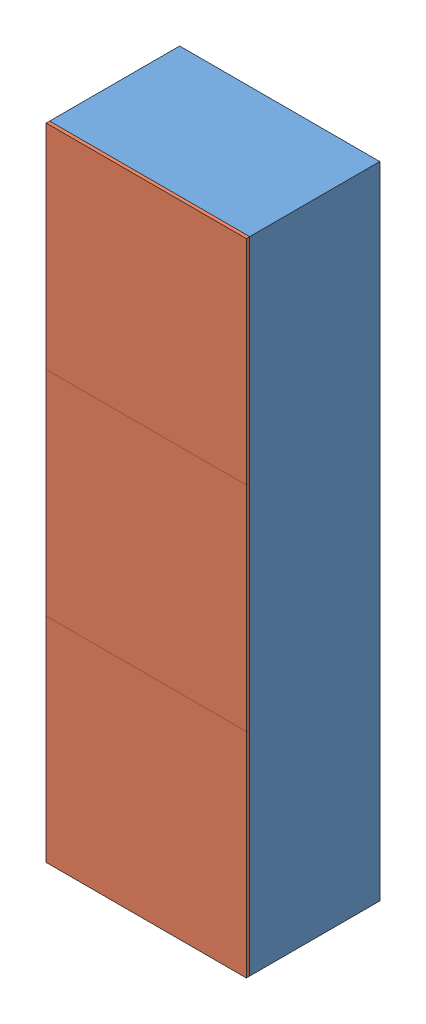
SolidWorks assembly Schrank-R, configuration Standard. Lengths in mm.
Overall size (600 1920 400).
6 component instances, 3 part files, 15 mates.
Components (placement in the parent):
- Schrank-Korpus-1: Schrank-Korpus [Standard] at (68.177 -29.4401 1725) size (600 1920 390)
- Türe-1: Türe [Standard] at (68.177 -669.4401 2115) size (600 640 10)
- Türe-2: Türe [Standard] at (68.177 -29.4401 2115) size (600 640 10)
- Türe-3: Türe [Standard] at (68.177 610.5599 2115) size (600 640 10)
- Regalbrett-1: Regalbrett [Standard] at (68.177 -354.4401 2095) x (1 0 0) z (0 1 0) size (560 360 10)
- Regalbrett-2: Regalbrett [Standard] at (68.177 285.5599 2095) x (1 0 0) z (0 1 0) size (560 360 10)
Mates (geometry in assembly coordinates):
- Deckungsgleich1: coincident: plane of Schrank-Korpus-1 through (68.177 -29.4401 1735) normal (0 0 1); plane of Regalbrett-2 through (68.177 285.5599 1735) normal (0 0 -1)
- Deckungsgleich2: coincident anti-aligned: plane of Schrank-Korpus-1 through (-211.823 910.5599 2115) normal (1 0 0); plane of Regalbrett-2 through (-211.823 290.5599 1735) normal (-1 0 0)
- Deckungsgleich3: coincident anti-aligned: plane of Schrank-Korpus-1 through (68.177 -29.4401 1735) normal (0 0 1); plane of Regalbrett-1 through (68.177 -354.4401 1735) normal (0 0 -1)
- Deckungsgleich4: coincident anti-aligned: plane of Schrank-Korpus-1 through (-211.823 910.5599 2115) normal (1 0 0); plane of Regalbrett-1 through (-211.823 -349.4401 1735) normal (-1 0 0)
- Deckungsgleich5: coincident aligned: plane of Schrank-Korpus-1 through (368.177 -989.4401 1735) normal (1 0 0); plane of Türe-1 through (368.177 -989.4401 2125) normal (1 0 0)
- Deckungsgleich6: coincident aligned: plane of Schrank-Korpus-1 through (-231.823 -989.4401 1735) normal (0 -1 0); plane of Türe-1 through (-231.823 -989.4401 2125) normal (0 -1 0)
- Deckungsgleich7: coincident: plane of Schrank-Korpus-1 through (368.177 -989.4401 1735) normal (1 0 0); plane of Türe-2 through (368.177 -349.4401 2125) normal (1 0 0)
- Deckungsgleich8: coincident anti-aligned: plane of Türe-1 through (-231.823 -349.4401 2125) normal (0 1 0); plane of Türe-2 through (-231.823 -349.4401 2125) normal (0 -1 0)
- Deckungsgleich9: coincident: plane of Schrank-Korpus-1 through (368.177 -989.4401 1735) normal (1 0 0); plane of Türe-3 through (368.177 290.5599 2125) normal (1 0 0)
- Deckungsgleich10: coincident: plane of Türe-2 through (-231.823 290.5599 2125) normal (0 1 0); plane of Türe-3 through (-231.823 290.5599 2125) normal (0 -1 0)
- Deckungsgleich11: coincident anti-aligned: plane of Schrank-Korpus-1 through (68.177 -29.4401 2115) normal (0 0 1); plane of Türe-1 through (68.177 -669.4401 2115) normal (0 0 -1)
- Deckungsgleich12: coincident: plane of Türe-1 through (-231.823 -349.4401 2125) normal (0 1 0); plane of Regalbrett-1 through (-211.823 -349.4401 1735) normal (0 1 0)
- Deckungsgleich13: coincident anti-aligned: plane of Schrank-Korpus-1 through (68.177 -29.4401 2115) normal (0 0 1); plane of Türe-2 through (68.177 -29.4401 2115) normal (0 0 -1)
- Deckungsgleich14: coincident aligned: plane of Türe-2 through (-231.823 290.5599 2125) normal (0 1 0); plane of Regalbrett-2 through (-211.823 290.5599 1735) normal (0 1 0)
- Deckungsgleich15: coincident anti-aligned: plane of Schrank-Korpus-1 through (68.177 -29.4401 2115) normal (0 0 1); plane of Türe-3 through (68.177 610.5599 2115) normal (0 0 -1)
